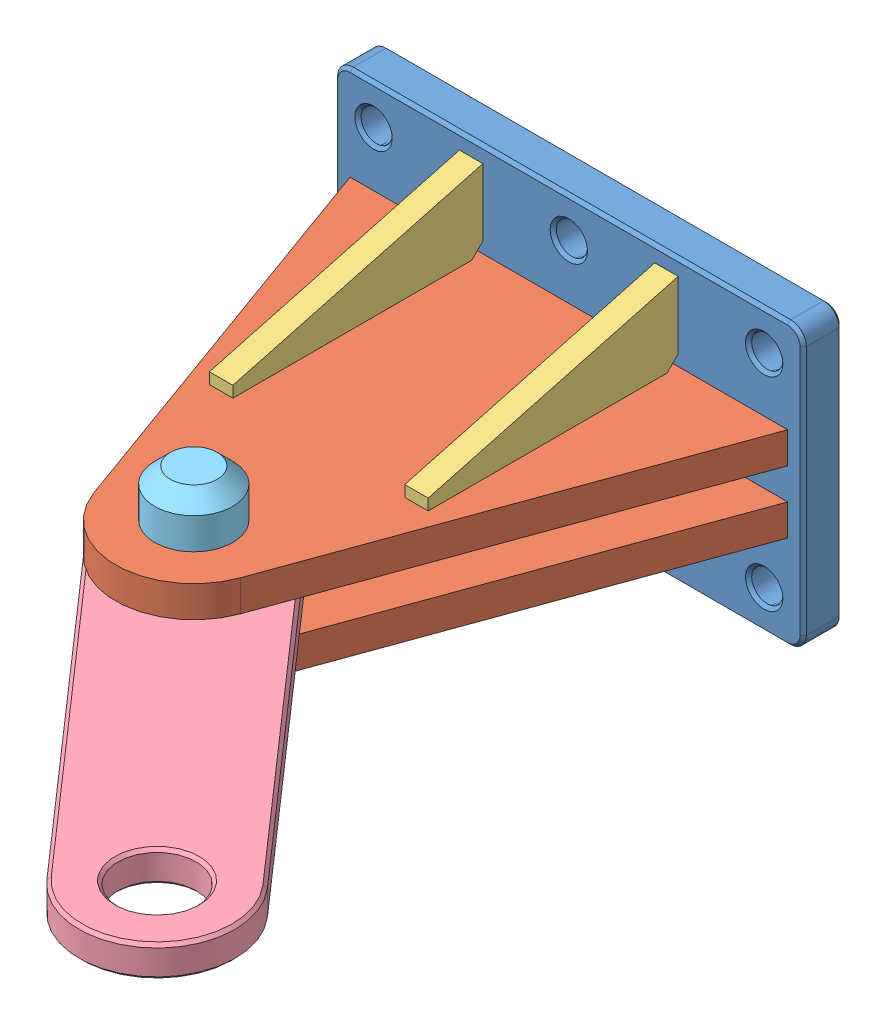
SolidWorks assembly assembly 2, configuration Default. Lengths in mm.
Overall size (388.75 180 527.23).
9 component instances, 5 part files, 13 mates.
Components (placement in the parent):
- hw2.1-1: hw2.1 [Default] at (109.9703 171.7512 233.5141) size (300 180 25)
- hw2.2-4: hw2.2 [Default] at (109.9703 141.7512 233.5141) x (1 0 0) z (0 -1 0) size (280 290 20)
- hw2.2-5: hw2.2 [Default] at (109.9703 201.7512 233.5141) x (-1 0 0) z (0 1 0) size (280 290 20)
- hw2.3-1: hw2.3 [Default] at (54.9703 141.7512 233.5141) x (0 1 0) z (1 0 0) size (50 160 15)
- hw2.3-2: hw2.3 [Default] at (179.9703 141.7512 233.5141) x (0 1 0) z (1 0 0) size (50 160 15)
- hw2.3-3: hw2.3 [Default] at (164.9703 201.7512 233.5141) x (0 -1 0) z (-1 0 0) size (50 160 15)
- hw2.3-4: hw2.3 [Default] at (39.9703 201.7512 233.5141) x (0 -1 0) z (-1 0 0) size (50 160 15)
- hw2.4-1: hw2.4 [Default] at (194.0628 181.7512 569.3509) x (-0.751661 0 0.659549) z (0 -1 0) size (100 355 20)
- hw2.5-1: hw2.5 [Default] at (109.9703 141.7512 473.5141) x (0 1 0) z (-0.295902 0 0.955218) size (120 80 80)
Mates (geometry in assembly coordinates):
- Distance1: distance = 20 mm: line of hw2.2-5 through (249.9703 181.7512 233.5141) axis (-1 0 0); line of hw2.2-4 through (-30.0297 161.7512 233.5141) axis (1 0 0)
- Symmetric2: symmetric aligned: plane of hw2.1-1 through (109.9703 171.7512 233.5141) normal (1 0 0); line of hw2.2-4 through (249.9703 161.7512 233.5141) axis (0 -1 0); line of hw2.2-4 through (-30.0297 161.7512 233.5141) axis (0 -1 0)
- Coincident10: coincident anti-aligned: plane of hw2.1-1 through (-30.0297 91.7512 233.5141) normal (0 0 1); plane of hw2.2-4 through (-30.0297 161.7512 233.5141) normal (0 0 -1)
- Coincident11: coincident anti-aligned: plane of hw2.1-1 through (-30.0297 91.7512 233.5141) normal (0 0 1); plane of hw2.3-1 through (39.9703 91.7512 233.5141) normal (0 0 -1)
- Coincident12: coincident anti-aligned: plane of hw2.2-4 through (109.9703 141.7512 473.5141) normal (0 -1 0); plane of hw2.3-1 through (39.9703 141.7512 393.5141) normal (0 1 0)
- Coincident13: coincident anti-aligned: plane of hw2.1-1 through (-30.0297 91.7512 233.5141) normal (0 0 1); plane of hw2.3-2 through (164.9703 91.7512 233.5141) normal (0 0 -1)
- Coincident14: coincident anti-aligned: plane of hw2.2-4 through (109.9703 141.7512 473.5141) normal (0 -1 0); plane of hw2.3-2 through (164.9703 141.7512 393.5141) normal (0 1 0)
- Distance2: distance = 110 mm: line of hw2.3-1 through (54.9703 91.7512 233.5141) axis (0 1 0); line of hw2.3-2 through (164.9703 91.7512 233.5141) axis (0 1 0)
- Symmetric3: symmetric aligned: plane of hw2.1-1 through (109.9703 171.7512 233.5141) normal (1 0 0); line of hw2.3-2 through (54.9703 91.7512 233.5141) axis (0 1 0); line of hw2.3-1 through (164.9703 91.7512 233.5141) axis (0 1 0)
- Concentric12: concentric aligned: cylinder of hw2.2-4 through (109.9703 161.7512 473.5141) axis (0 -1 0) radius 25; cylinder of hw2.5-1 through (109.9703 4.1261 473.5141) axis (0 -1 0) radius 25
- Coincident19: coincident anti-aligned: plane of hw2.2-4 through (109.9703 141.7512 473.5141) normal (0 -1 0); plane of hw2.5-1 through (148.179 141.7512 485.3502) normal (0 1 0)
- Concentric13: concentric anti-aligned: cylinder of hw2.4-1 through (109.9703 161.7512 473.5141) axis (0 1 0) radius 25; cylinder of hw2.5-1 through (109.9703 4.1261 473.5141) axis (0 -1 0) radius 25
- Width7: width anti-aligned: plane of hw2.2-5 through (109.9703 181.7512 473.5141) normal (0 -1 0); plane of hw2.4-1 through (109.9703 161.7512 473.5141) normal (0 1 0); plane of hw2.2-4 through (109.9703 181.7512 473.5141) normal (0 1 0); plane of hw2.4-1 through (109.9703 161.7512 473.5141) normal (0 -1 0)
